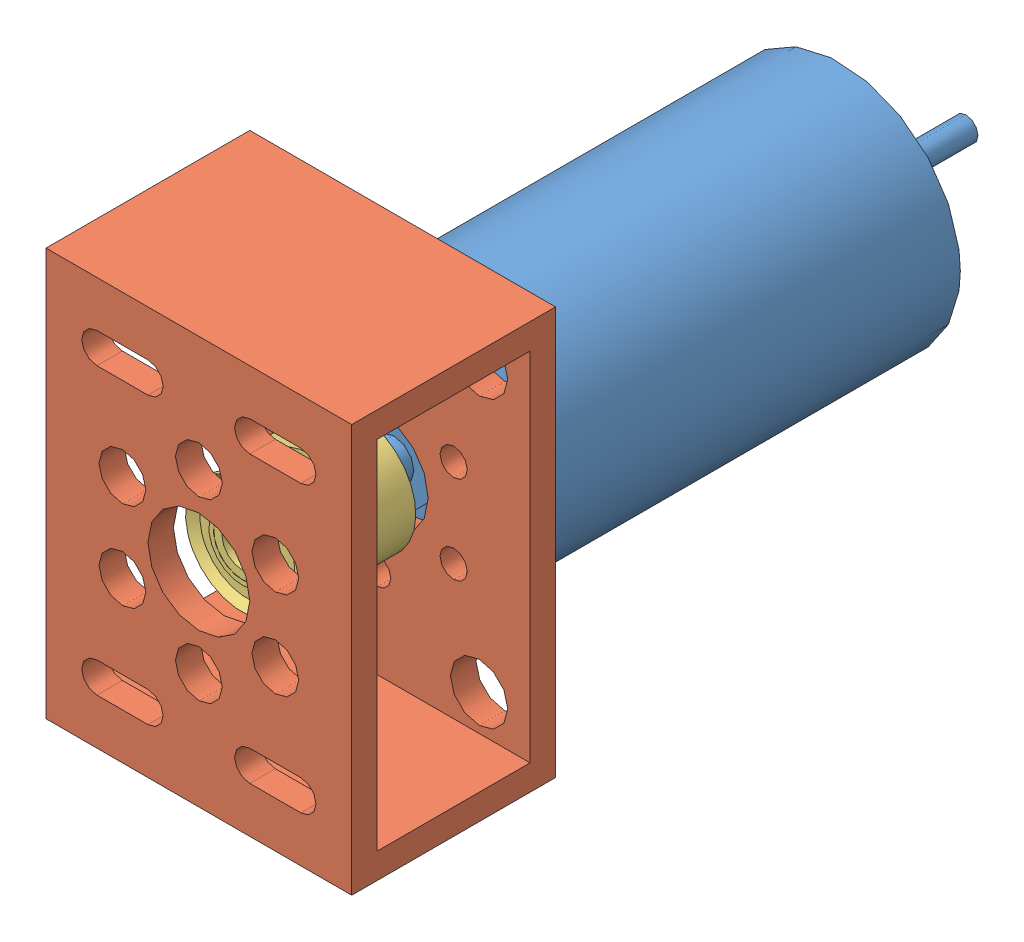
SolidWorks assembly motor-mount-asm, configuration Default. Lengths in mm.
Overall size (38.1 50.8 95.6).
3 component instances, 3 part files, 5 mates.
Components (placement in the parent):
- 000_maxon_Re30-1: 000_maxon_Re30 [Default] at origin size (30 30 83)
- y06-motor-mount-box-1: y06-motor-mount-box [Default] at (19.05 0 67.2) x (0 -1 0) z (-1 0 0) size (50.8 25.4 38.1)
- a_6d16m015df6005-5mmboresdp-ai-1: a_6d16m015df6005-5mmboresdp-ai [Default] at (0 0 66.215) x (-0.916849 -0.399235 0) z (0 0 -1) size (14.7 14.7 14.3)
Mates (geometry in assembly coordinates):
- Coincident1: coincident anti-aligned: plane of 000_maxon_Re30-1 through (0 0 54.5) normal (0 0 1); plane of y06-motor-mount-box-1 through (-19.05 25.4 54.5) normal (0 0 -1)
- Concentric1: concentric anti-aligned: cylinder of 000_maxon_Re30-1; cylinder of y06-motor-mount-box-1
- Concentric2: concentric aligned: cylinder of 000_maxon_Re30-1; cylinder of y06-motor-mount-box-1
- Concentric3: concentric aligned: cylinder of 000_maxon_Re30-1; cylinder of a_6d16m015df6005-5mmboresdp-ai-1
- Distance1: distance = 2.54 mm anti-aligned: plane of y06-motor-mount-box-1 through (-19.05 22.225 57.675) normal (0 0 1); plane of a_6d16m015df6005-5mmboresdp-ai-1 through (-2.9344 6.7388 60.215) normal (0 0 -1)
